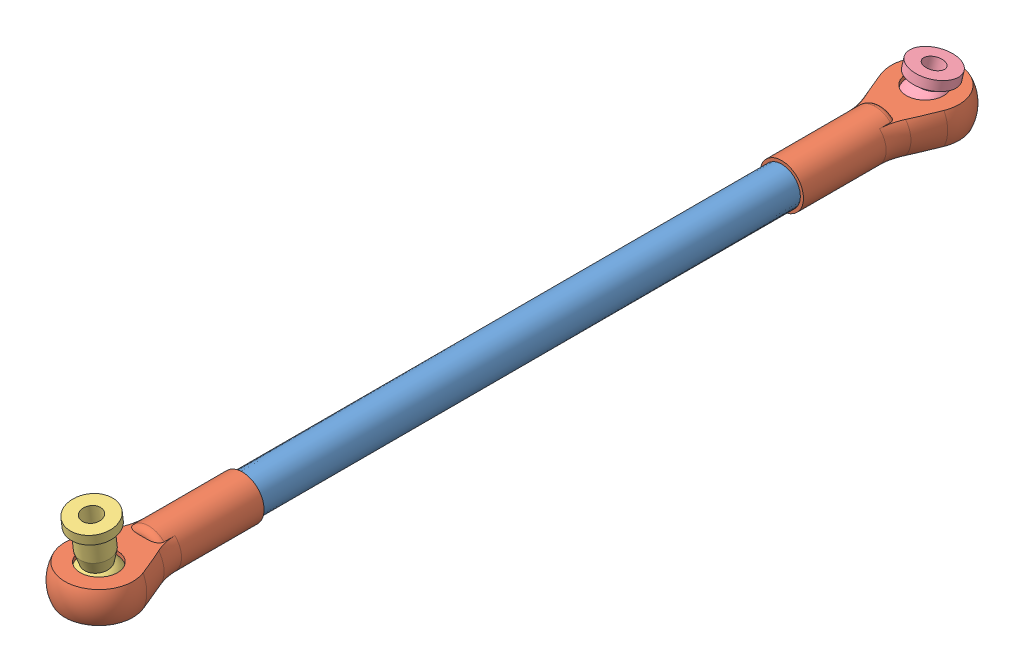
SolidWorks assembly Bar_2, configuration Default. Lengths in mm.
Overall size (12 15.2 144.5).
5 component instances, 4 part files, 8 mates.
Components (placement in the parent):
- Bar_2-1: Bar_2 [Default] at origin size (6 6 114.5)
- Ball_socket-1: Ball_socket [Default] at (0 0 115.5) x (0 -1 0) z (0 0 -1) size (7 12 29)
- Ball_socket-2: Ball_socket [Default] at (0 0 -1) x (0 -1 0) z (0 0 1) size (7 12 29)
- Ball_1-1: Ball_1 [Default] at (-0.11 -3.3326 122.9963) x (0.99812 -0.039975 0.046453) z (-0.032628 -0.988243 -0.149367) size (7 7 13.5)
- Ball_2-1: Ball_2 [Default] at (-0.3496 -3.5554 -8.3695) x (0.980513 -0.123503 -0.152777) z (-0.096365 -0.980055 0.173801) size (7 7 9)
Mates (geometry in assembly coordinates):
- Concentric1: concentric aligned: cylinder of Bar_2-1 through (0 0 114.5) axis (0 0 -1) radius 3; cylinder of Ball_socket-2 through (0 0 14) axis (0 0 -1) radius 3
- Concentric2: concentric anti-aligned: cylinder of Bar_2-1 through (0 0 114.5) axis (0 0 -1) radius 3; cylinder of Ball_socket-1 through (0 0 100.5) axis (0 0 1) radius 3
- Parallel1: parallel aligned: plane of Ball_socket-1 through (17.5 2.5 115.5) normal (0 1 0); plane of Ball_socket-2 through (-17.5 2.5 -1) normal (0 1 0)
- Parallel2: parallel aligned: plane of Ball_socket-1 through (17.5 2.5 115.5) normal (0 1 0); plane of assembly through (0 0 0) normal (0 1 0)
- Coincident3: coincident anti-aligned: plane of Bar_2-1 through (0 0 0) normal (0 0 -1); plane of Ball_socket-2 through (0 0 0) normal (0 0 1)
- Coincident4: coincident anti-aligned: plane of Bar_2-1 through (0 0 114.5) normal (0 0 1); plane of Ball_socket-1 through (0 0 114.5) normal (0 0 -1)
- Concentric3: concentric: sphere of Ball_socket-1; sphere of Ball_1-1
- Concentric4: concentric: sphere of Ball_socket-2; sphere of Ball_2-1
